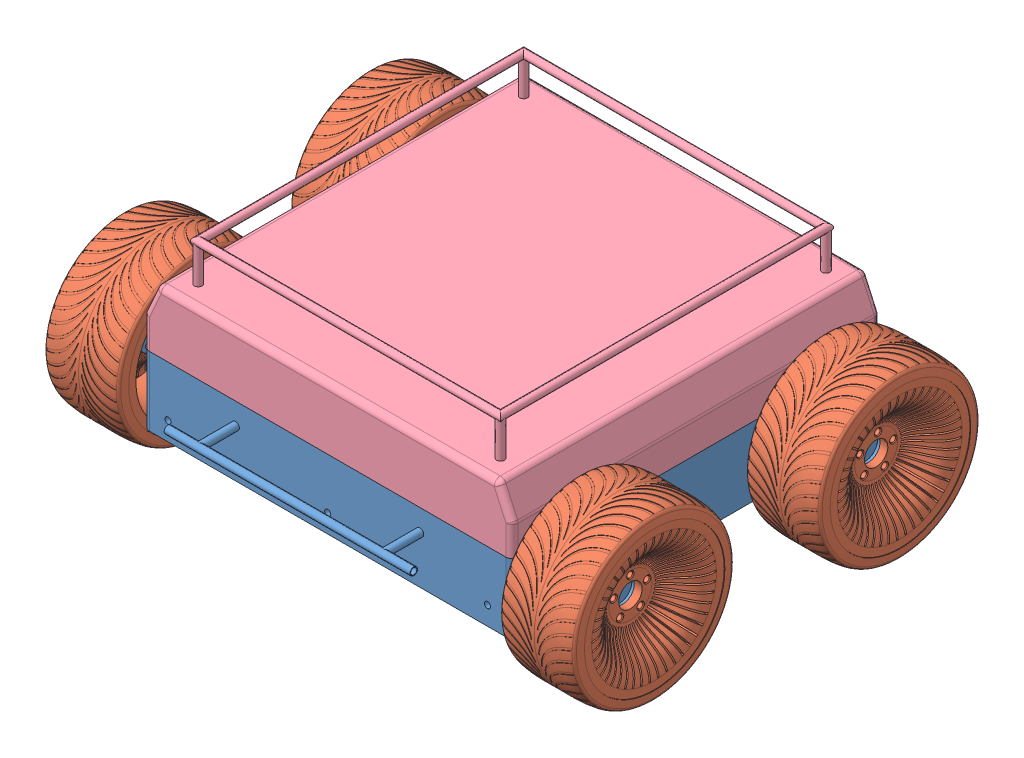
SolidWorks assembly updated base and wheels assembly - Copy, configuration Default. Lengths in mm.
Overall size (1744.11 737.37 1465).
11 component instances, 5 part files, 28 mates.
Components (placement in the parent):
- BASE - Copy-2: BASE - Copy [Default<As Machined>] at (827.8363 661.6568 1059.2236) size (1520 225 1465)
- 18 x 9.5 wheel-3: 18 x 9.5 wheel [Default] at (1587.8363 756.6568 659.2236) x (1 0 0) z (0 0.112104 0.993697) size (252.9 542.37 542.37)
- 18 x 9.5 wheel-4: 18 x 9.5 wheel [Default] at (1587.8363 756.6568 1459.2236) size (252.9 542.37 542.37)
- 18 x 9.5 wheel-5: 18 x 9.5 wheel [Default] at (67.8363 756.6568 659.2236) x (-1 0 0) z (0 0 -1) size (252.9 542.37 542.37)
- 18 x 9.5 wheel-6: 18 x 9.5 wheel [Default] at (67.8363 756.6568 1459.2236) x (-1 0 0) z (0 0 -1) size (252.9 542.37 542.37)
- chassis-1: chassis [Default<As Machined>] at (1295.9851 766.5317 2607.767) size (1075 344.87 1105) (hidden)
- Motenergy ME1114-1: Motenergy ME1114 [Default] at (405.8363 756.6568 659.2236) x (0 -1 -0.000674) z (-1 0 0) size (200 240 212.88)
- Motenergy ME1114-2: Motenergy ME1114 [Default] at (1229.8363 756.6568 1459.8036) x (0 -1 0) z (1 0 0) size (200 240 212.88)
- Motenergy ME1114-3: Motenergy ME1114 [Default] at (1229.8363 756.6568 658.6436) x (0 1 0) z (1 0 0) size (200 240 212.88)
- Motenergy ME1114-4: Motenergy ME1114 [Default] at (405.8363 756.6568 1459.8036) x (0 -1 0) z (-1 0 0) size (200 240 212.88)
- top-2: top [Default<As Machined>] at (827.8363 789.6568 459.2236) size (1200 332.5 1200)
Mates (geometry in assembly coordinates):
- Concentric3: concentric: circle of BASE - Copy-2; circle of 18 x 9.5 wheel-3
- Coincident5: coincident: plane of BASE - Copy-2 through (1587.8363 756.6568 659.2236) normal (1 0 0); plane of 18 x 9.5 wheel-3 through (1587.8363 832.8295 650.6302) normal (-1 0 0)
- Parallel3: parallel: cylinder of BASE - Copy-2 through (1577.8363 774.3187 713.5813) axis (1 0 0) radius 9.525; cylinder of 18 x 9.5 wheel-3 through (1448.9259 813.4466 652.8169) axis (1 0 0) radius 9.525
- Concentric5: concentric: circle of BASE - Copy-2; circle of 18 x 9.5 wheel-4
- Coincident6: coincident: plane of BASE - Copy-2 through (1587.8363 756.6568 1459.2236) normal (1 0 0); plane of 18 x 9.5 wheel-4 through (1587.8363 833.3127 1459.2236) normal (-1 0 0)
- Concentric6: concentric: circle of BASE - Copy-2; circle of 18 x 9.5 wheel-5
- Coincident7: coincident: plane of BASE - Copy-2 through (67.8363 756.6568 659.2236) normal (-1 0 0); plane of 18 x 9.5 wheel-5 through (67.8363 833.3127 659.2236) normal (1 0 0)
- Coincident9: coincident: cylinder of BASE - Copy-2 through (67.8363 774.3171 604.8707) axis (1 0 0) radius 9.525; circle of 18 x 9.5 wheel-5
- Coincident10: coincident: plane of BASE - Copy-2 through (67.8363 756.6568 1459.2236) normal (-1 0 0); plane of 18 x 9.5 wheel-6 through (67.8363 833.3127 1459.2236) normal (1 0 0)
- Concentric7: concentric: circle of BASE - Copy-2; circle of 18 x 9.5 wheel-6
- Distance5: distance = 0 mm: cylinder of Motenergy ME1114-1 through (386.2363 756.6568 659.2236) axis (-1 0 0) radius 11.115; cylinder of BASE - Copy-2 through (377.8363 756.6568 659.2236) axis (-1 0 0) radius 20
- Distance6: distance = 45 mm: plane of Motenergy ME1114-1 through (392.8363 756.6298 699.2236) normal (-1 0 0); plane of BASE - Copy-2 through (347.8363 756.6568 659.2236) normal (1 0 0)
- Distance8: distance = 45 mm: plane of BASE - Copy-2 through (247.8363 861.6568 479.2236) normal (1 0 0); line of chassis-1 through (292.8363 756.6568 1419.2236) axis (0 0 -1)
- Concentric10: concentric: circle of BASE - Copy-2; circle of chassis-1
- Coincident21: coincident: cylinder of BASE - Copy-2 through (1307.8363 756.6568 659.2236) axis (1 0 0) radius 40; circle of chassis-1
- Coincident24: coincident: plane of chassis-1 through (1295.9851 766.5317 1579.8036) normal (0 0 -1); plane of Motenergy ME1114-2 through (1229.8363 756.6568 1579.8036) normal (0 0 1)
- Coincident25: coincident: plane of chassis-1 through (1135.2363 801.6568 1579.8036) normal (-1 0 0); plane of Motenergy ME1114-2 through (1135.2363 801.6568 1339.8026) normal (-1 0 0)
- Coincident31: coincident: plane of chassis-1 through (1295.9851 766.5317 538.6436) normal (0 0 1); plane of Motenergy ME1114-3 through (1229.8363 756.6568 538.6436) normal (0 0 -1)
- Coincident32: coincident: plane of chassis-1 through (1135.2363 801.6568 538.6436) normal (0 1 0); plane of Motenergy ME1114-3 through (1190.2363 801.6568 778.6446) normal (0 1 0)
- Coincident33: coincident: plane of chassis-1 through (1135.2363 801.6568 538.6436) normal (-1 0 0); plane of Motenergy ME1114-3 through (1135.2363 711.6568 778.6446) normal (-1 0 0)
- Parallel11: parallel: plane of chassis-1 through (1295.9851 801.6568 2607.767) normal (0 1 0); plane of Motenergy ME1114-3 through (1190.2363 801.6568 558.4726) normal (0 1 0)
- Distance13: distance = 0 mm: plane of Motenergy ME1114-4 through (405.8363 756.6568 1579.8036) normal (0 0 1); plane of chassis-1 through (1295.9851 766.5317 1579.8036) normal (0 0 -1)
- Coincident36: coincident: plane of chassis-1 through (1295.9851 801.6568 2607.767) normal (0 1 0); plane of Motenergy ME1114-4 through (445.4363 801.6568 1579.8046) normal (0 1 0)
- Coincident37: coincident: plane of chassis-1 through (500.4363 711.6568 2607.767) normal (1 0 0); plane of Motenergy ME1114-4 through (500.4363 801.6568 1579.8046) normal (1 0 0)
- Coincident38: coincident: plane of BASE - Copy-2 through (1407.8363 861.6568 1639.2236) normal (0 1 0); plane of top-2 through (1427.8363 861.6568 1639.2236) normal (0 -1 0)
- Coincident39: coincident: plane of BASE - Copy-2 through (247.8363 861.6568 1659.2236) normal (0 0 1); plane of top-2 through (827.8363 789.6568 1659.2236) normal (0 0 1)
- Coincident40: coincident: plane of BASE - Copy-2 through (1427.8363 861.6568 479.2236) normal (1 0 0); plane of top-2 through (1427.8363 861.6568 1639.2236) normal (1 0 0)
- Coincident41: coincident: plane of chassis-1 through (1295.9851 801.6568 2607.767) normal (0 1 0); plane of Motenergy ME1114-2 through (1190.2363 801.6568 1559.9746) normal (0 1 0)
